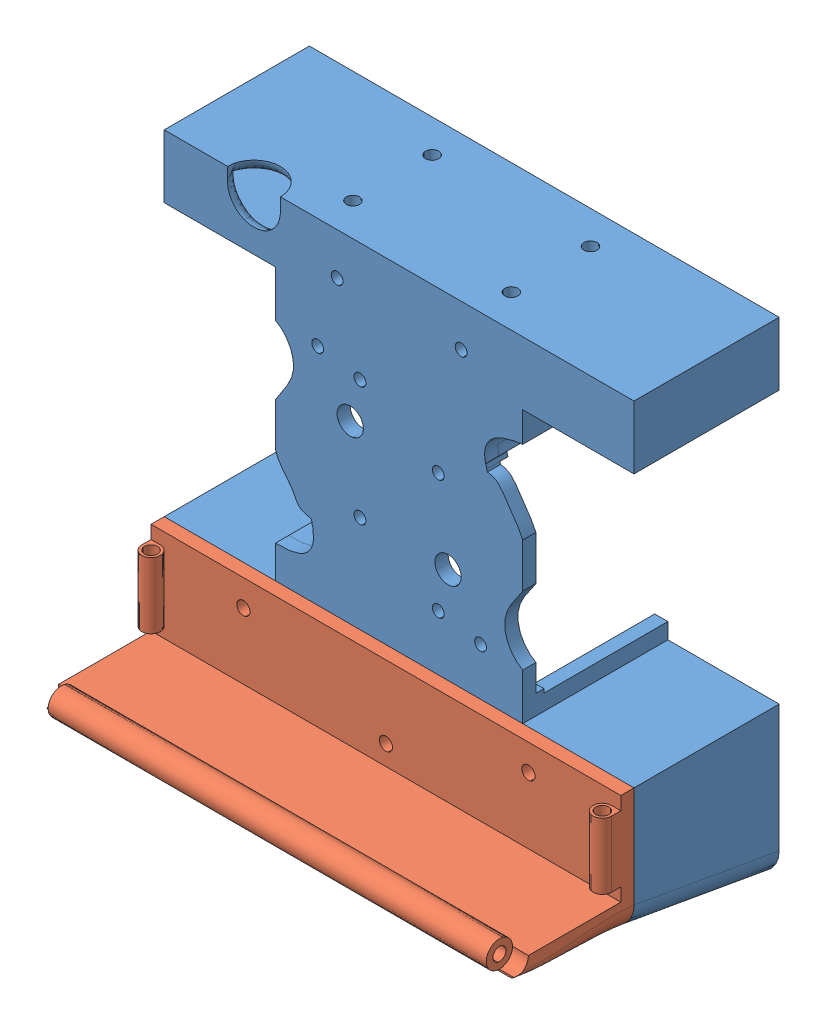
SolidWorks assembly Assem1, configuration Default. Lengths in mm.
Overall size (179.15 185.55 105).
2 component instances, 2 part files, 3 mates.
Components (placement in the parent):
- Dolly chassis half 1-1: Dolly chassis half 1 [Default] at (30.2827 230.0918 72.4602) size (178 185.55 55.53)
- Foldable front base 2-1: Foldable front base 2 [Default] at (119.2816 -41.1603 77.4602) x (1 0 0) z (0 -1 0) size (179.15 52.01 49.18)
Mates (geometry in assembly coordinates):
- Coincident1: coincident: plane of Dolly chassis half 1-1 through (30.2827 230.0918 77.4602) normal (0 0 1); plane of Foldable front base 2-1 through (119.2816 -41.1603 77.4602) normal (0 0 -1)
- Coincident2: coincident: plane of Dolly chassis half 1-1 through (119.2816 230.0918 72.4602) normal (1 0 0); plane of Foldable front base 2-1 through (119.2816 -41.1603 122.4602) normal (1 0 0)
- Coincident3: coincident: plane of Dolly chassis half 1-1 through (175.13 -41.1603 77.4602) normal (0 -0.984808 0.173648); plane of Foldable front base 2-1 through (119.2816 -41.1603 77.4602) normal (0 -0.984808 0.173648)
